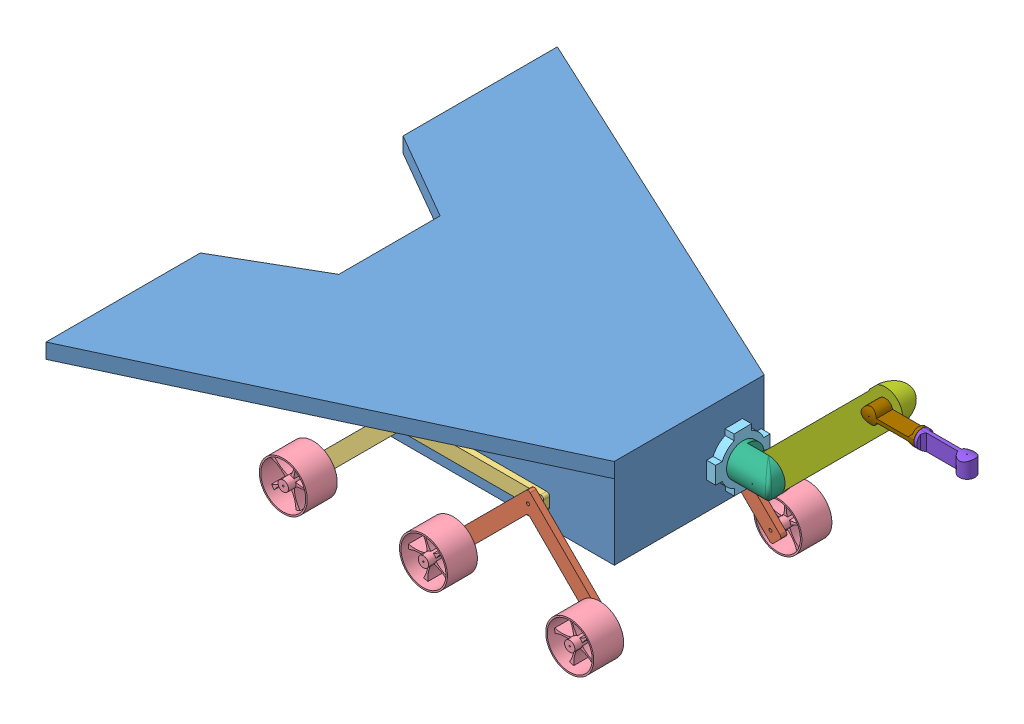
SolidWorks assembly IntrepidAssembly, configuration Default. Lengths in mm.
Overall size (2131.54 1151 1705.65).
18 component instances, 9 part files, 29 mates.
Components (placement in the parent):
- RoverBody-1: RoverBody [Default] at (1058.7586 896.3003 1082.289) size (1292.76 300 1705.65)
- 2WheelBase-1: 2WheelBase [Default] at (535.2452 486.6452 1109.289) x (0.707107 -0.707107 0) z (0 0 1) size (400 400 20)
- WheelBase-1: WheelBase [Default] at (848.088 702.0615 1107.289) x (0 0 -1) z (1 0 0) size (20 333.58 798.23)
- 2WheelBase-3: 2WheelBase [Default] at (535.2452 486.6452 544.789) x (0.707107 -0.707107 0) z (0 0 1) size (400 400 20)
- WheelBase-3: WheelBase [Default] at (848.088 702.0615 587.289) x (0 0 -1) z (1 0 0) size (20 333.58 798.23)
- roverTire-1: roverTire [Default] at (84.6112 453.2293 1212.289) x (0 0 -1) z (0.015644 -0.999878 0) size (100 160 160)
- roverTire-2: roverTire [Default] at (574.1361 490.1807 1234.289) x (0 0 -1) z (0.923564 0.383443 0) size (100 160 160)
- roverTire-3: roverTire [Default] at (1062.0398 490.1807 1234.289) x (0 0 -1) z (0.930456 0.366405 0) size (100 160 160)
- roverTire-4: roverTire [Default] at (84.6112 453.2293 462.289) x (0 0 1) z (-0.998135 0.061045 0) size (100 160 160)
- roverTire-5: roverTire [Default] at (1062.0398 490.1807 439.789) x (0 0 1) z (-0.999998 -0.001767 0) size (100 160 160)
- roverTire-6: roverTire [Default] at (574.1361 490.1807 439.789) x (0 0 1) z (-1 0 0) size (100 160 160)
- armassembly-1: armassembly [Default] at (1087.4726 753.9359 681.8229) x (0 -0.382683 0.92388) z (-1 0 0) size (324.73 558.08 846.27) (flexible)
  - armbase-1: armbase [Default] at (-3.793 12.8281 -1.286) size (190 188.21 30)
  - Arm Shoulder-1: Arm Shoulder [Default] at (-3.793 12.8281 -1.786) x (0.382683 -0.92388 0) z (0 0 -1) size (110 110 140)
  - LowerArm-1: LowerArm [Default] at (-158.8584 385.8824 -559.3447) x (-0.376605 0.909205 0.177522) z (-0.92388 -0.382683 0) size (429.57 567.65 63.91)
  - upperarmassembly-1: upperarmassembly [Default] at (-80.7861 379.3987 -688.319) x (0.844945 0.349988 0.404445) z (-0.382683 0.92388 0) size (185.69 343.24 172.56) (flexible)
    - UpperArmtop-1: UpperArmtop [Default] at (-74.0027 148.359 -6.3156) size (111.7 174.07 56.17)
    - UpperArmbottom-1: UpperArmbottom [Default] at (54.1953 -293.5207 55.1556) x (-0.163576 0.36989 0.914562) z (0.914562 0.404445 0) size (111.7 174.07 56.17)
Mates (geometry in assembly coordinates):
- Distance1: distance = 5 mm anti-aligned: plane of WheelBase-1 through (848.088 702.0615 1087.289) normal (0 0 -1); plane of RoverBody-1 through (1058.7586 646.3003 1082.289) normal (0 0 1)
- Distance2: distance = 2 mm anti-aligned: plane of 2WheelBase-1 through (535.2452 486.6452 1109.289) normal (0 0 -1); plane of WheelBase-1 through (848.088 702.0615 1107.289) normal (0 0 1)
- Concentric2: concentric anti-aligned: cylinder of 2WheelBase-1 through (818.088 727.0615 1109.289) axis (0 0 1) radius 5; cylinder of WheelBase-1 through (818.088 727.0615 1107.289) axis (0 0 -1) radius 5
- Distance5: distance = 5 mm anti-aligned: plane of WheelBase-3 through (848.088 702.0615 587.289) normal (0 0 1); plane of RoverBody-1 through (1058.7586 646.3003 582.289) normal (0 0 -1)
- Concentric4: concentric anti-aligned: cylinder of 2WheelBase-3 through (818.088 727.0615 544.789) axis (0 0 1) radius 5; cylinder of WheelBase-3 through (818.088 727.0615 587.289) axis (0 0 -1) radius 5
- Distance6: distance = 2.5 mm anti-aligned: plane of 2WheelBase-3 through (535.2452 486.6452 564.789) normal (0 0 1); plane of WheelBase-3 through (848.088 702.0615 567.289) normal (0 0 -1)
- Concentric5: concentric anti-aligned: cylinder of RoverBody-1 through (358.7586 726.3003 568.1468) axis (0 0 1) radius 5; cylinder of WheelBase-3 through (358.7586 726.3003 587.289) axis (0 0 -1) radius 5
- Concentric6: concentric anti-aligned: cylinder of RoverBody-1 through (358.7586 726.3003 568.1468) axis (0 0 1) radius 5; cylinder of WheelBase-1 through (358.7586 726.3003 1107.289) axis (0 0 -1) radius 5
- Concentric7: concentric anti-aligned: cylinder of WheelBase-1 through (84.6112 453.2293 1107.289) axis (0 0 -1) radius 5; circle of roverTire-1
- Distance7: distance = 5 mm anti-aligned: plane of roverTire-1 through (84.6112 453.2293 1112.289) normal (0 0 -1); plane of WheelBase-1 through (848.088 702.0615 1107.289) normal (0 0 1)
- Concentric8: concentric aligned: cylinder of 2WheelBase-1 through (588.2581 476.4558 1109.289) axis (0 0 1) radius 5; cylinder of roverTire-2 through (588.2581 476.4558 1134.289) axis (0 0 1) radius 2.5
- Distance8: distance = 5 mm anti-aligned: plane of roverTire-2 through (574.1361 490.1807 1134.289) normal (0 0 -1); plane of 2WheelBase-1 through (535.2452 486.6452 1129.289) normal (0 0 1)
- Concentric9: concentric aligned: cylinder of 2WheelBase-1 through (1075.3435 504.7001 1109.289) axis (0 0 1) radius 5; cylinder of roverTire-3 through (1075.3435 504.7001 1134.289) axis (0 0 1) radius 2.5
- Distance9: distance = 5 mm anti-aligned: plane of roverTire-3 through (1062.0398 490.1807 1134.289) normal (0 0 -1); plane of 2WheelBase-1 through (535.2452 486.6452 1129.289) normal (0 0 1)
- Concentric10: concentric anti-aligned: circle of 2WheelBase-3; cylinder of roverTire-5 through (1075.3435 504.7001 539.789) axis (0 0 -1) radius 2.5
- Distance10: distance = 5 mm anti-aligned: plane of roverTire-5 through (1062.0398 490.1807 539.789) normal (0 0 1); plane of 2WheelBase-3 through (535.2452 486.6452 544.789) normal (0 0 -1)
- Concentric11: concentric anti-aligned: cylinder of 2WheelBase-3 through (588.2581 476.4558 544.789) axis (0 0 1) radius 5; cylinder of roverTire-6 through (588.2581 476.4558 539.789) axis (0 0 -1) radius 2.5
- Distance11: distance = 5 mm anti-aligned: plane of roverTire-6 through (574.1361 490.1807 539.789) normal (0 0 1); plane of 2WheelBase-3 through (535.2452 486.6452 544.789) normal (0 0 -1)
- Distance12: distance = 5 mm anti-aligned: plane of roverTire-4 through (84.6112 453.2293 562.289) normal (0 0 1); plane of WheelBase-3 through (848.088 702.0615 567.289) normal (0 0 -1)
- Concentric12: concentric aligned: cylinder of WheelBase-3 through (84.6112 453.2293 587.289) axis (0 0 -1) radius 5; cylinder of roverTire-4 through (84.6112 453.2293 562.289) axis (0 0 -1) radius 2.5
- Coincident1: coincident anti-aligned: plane of RoverBody-1 through (1058.7586 946.3003 1082.289) normal (1 0 0); plane of armassembly-1/armbase-1 through (1058.7586 767.2391 683.2278) normal (-1 0 0)
- Distance13: distance = 10 mm aligned: plane of armassembly-1/armbase-1 through (1163.0623 767.2391 592.289) normal (0 0 -1); plane of RoverBody-1 through (1058.7586 646.3003 582.289) normal (0 0 -1)
- Distance14: distance = 30 mm aligned: plane of RoverBody-1 through (1058.7586 646.3003 1082.289) normal (0 -1 0); plane of armassembly-1/armbase-1 through (1163.0623 676.3003 683.2278) normal (0 -1 0)
- Concentric13: concentric anti-aligned: cylinder of roverTire-3 through (1075.3435 504.7001 1134.289) axis (0 0 1) radius 2.5; cylinder of roverTire-5 through (1075.3435 504.7001 539.789) axis (0 0 -1) radius 2.5
- Parallel3: parallel aligned: plane of RoverBody-1 through (1058.7586 646.3003 582.289) normal (0 0 -1); plane of armassembly-1/Arm Shoulder-1 through (1174.2586 767.2391 683.2278) normal (0 0 -1)
- Angle1: planar angle = 0.785398 rad anti-aligned: plane of armassembly-1/LowerArm-1 through (1154.9761 821.8769 682.7278) normal (-0.707107 0.707107 0); plane of RoverBody-1 through (1058.7586 946.3003 1082.289) normal (1 0 0)
- Parallel5: parallel aligned: plane of RoverBody-1 through (1058.7586 946.3003 1082.289) normal (0 1 0); plane of armassembly-1/upperarmassembly-1/UpperArmbottom-1 through (1713.1673 1162.0109 683.2278) normal (0 1 0)
- Parallel6: parallel aligned: plane of RoverBody-1 through (1058.7586 646.3003 1082.289) normal (0 -1 0); plane of WheelBase-1 through (848.088 702.0615 1087.289) normal (0 -1 0)
- Parallel7: parallel aligned: plane of 2WheelBase-1 through (570.6006 451.2898 1129.289) normal (0.707107 -0.707107 0); plane of WheelBase-1 through (608.4433 941.7061 1087.289) normal (0.707107 -0.707107 0)
